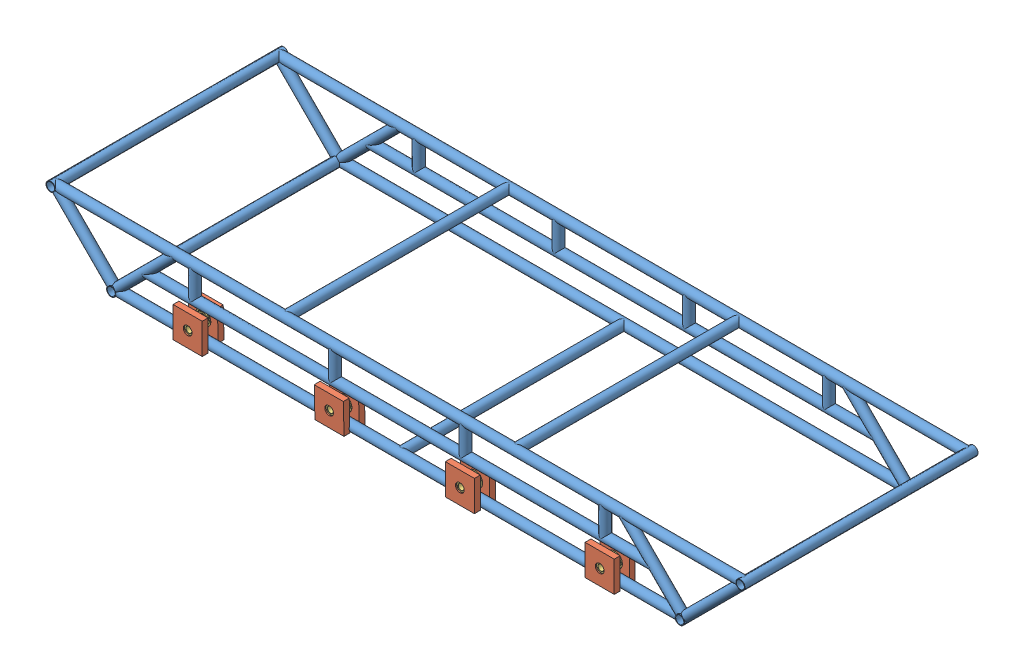
SolidWorks assembly Bodenwanne, configuration Standard. Lengths in mm.
Overall size (1200 120.5 410).
25 component instances, 3 part files, 5 mates.
Components (placement in the parent):
- Ramen Bodenwanne-1: Ramen Bodenwanne [Standard<Wie bearbeitet>] at (-1765.5754 89.1394 1497.5) size (1200 120 400)
- Lagerklotz-1: Lagerklotz [Standard] at (-1456.198 11.0005 1431.2566) x (1 0 0) z (0 -0.027484 0.999622) size (50 52.5 10)
  - Lagerklotz-1: Lagerklotz [Standard] at (-89.1989 -26.6804 47.5) size (50 52.5 10)
  - radial ball bearing_68_din-1: radial ball bearing_68_din [DIN 625 - 6000 - 8,DE,NC,8_68] at (-64.1989 -0.4304 53.5) x (0 0 -1) z (1 0 0) size (8 26 26)
- Lagerklotz-2: Lagerklotz [Standard] at (-1213.9871 4.5623 1431.2898) x (1 0 0) z (0 -0.021338 0.999772) size (50 52.5 10)
  - Lagerklotz-1: Lagerklotz [Standard] at (-89.1989 -26.6804 47.5) size (50 52.5 10)
  - radial ball bearing_68_din-1: radial ball bearing_68_din [DIN 625 - 6000 - 8,DE,NC,8_68] at (-64.1989 -0.4304 53.5) x (0 0 -1) z (1 0 0) size (8 26 26)
- Lagerklotz-3: Lagerklotz [Standard] at (-988.8766 3.3198 1432) size (50 52.5 10)
  - Lagerklotz-1: Lagerklotz [Standard] at (-89.1989 -26.6804 47.5) size (50 52.5 10)
  - radial ball bearing_68_din-1: radial ball bearing_68_din [DIN 625 - 6000 - 8,DE,NC,8_68] at (-64.1989 -0.4304 53.5) x (0 0 -1) z (1 0 0) size (8 26 26)
- Lagerklotz-4: Lagerklotz [Standard] at (-748.8766 3.3198 1432) size (50 52.5 10)
  - Lagerklotz-1: Lagerklotz [Standard] at (-89.1989 -26.6804 47.5) size (50 52.5 10)
  - radial ball bearing_68_din-1: radial ball bearing_68_din [DIN 625 - 6000 - 8,DE,NC,8_68] at (-64.1989 -0.4304 53.5) x (0 0 -1) z (1 0 0) size (8 26 26)
- Lagerklotz-5: Lagerklotz [Standard] at (-1584.5957 3.3198 1563) x (-1 0 0) z (0 0 -1) size (50 52.5 10)
  - Lagerklotz-1: Lagerklotz [Standard] at (-89.1989 -26.6804 47.5) size (50 52.5 10)
  - radial ball bearing_68_din-1: radial ball bearing_68_din [DIN 625 - 6000 - 8,DE,NC,8_68] at (-64.1989 -0.4304 53.5) x (0 0 -1) z (1 0 0) size (8 26 26)
- Lagerklotz-6: Lagerklotz [Standard] at (-1342.3849 3.9862 1562.3073) x (-1 0 0) z (0 0.021338 -0.999772) size (50 52.5 10)
  - Lagerklotz-1: Lagerklotz [Standard] at (-89.1989 -26.6804 47.5) size (50 52.5 10)
  - radial ball bearing_68_din-1: radial ball bearing_68_din [DIN 625 - 6000 - 8,DE,NC,8_68] at (-64.1989 -0.4304 53.5) x (0 0 -1) z (1 0 0) size (8 26 26)
- Lagerklotz-7: Lagerklotz [Standard] at (-1117.2743 3.3198 1563) x (-1 0 0) z (0 0 -1) size (50 52.5 10)
  - Lagerklotz-1: Lagerklotz [Standard] at (-89.1989 -26.6804 47.5) size (50 52.5 10)
  - radial ball bearing_68_din-1: radial ball bearing_68_din [DIN 625 - 6000 - 8,DE,NC,8_68] at (-64.1989 -0.4304 53.5) x (0 0 -1) z (1 0 0) size (8 26 26)
- Lagerklotz-8: Lagerklotz [Standard] at (-877.2743 3.3198 1563) x (-1 0 0) z (0 0 -1) size (50 52.5 10)
  - Lagerklotz-1: Lagerklotz [Standard] at (-89.1989 -26.6804 47.5) size (50 52.5 10)
  - radial ball bearing_68_din-1: radial ball bearing_68_din [DIN 625 - 6000 - 8,DE,NC,8_68] at (-64.1989 -0.4304 53.5) x (0 0 -1) z (1 0 0) size (8 26 26)
Mates (geometry in assembly coordinates):
- Deckungsgleich27: coincident aligned: plane of Lagerklotz-4/Lagerklotz-1 through (-788.0754 29.1394 1489.5) normal (1 0 0); plane of Lagerklotz-8/Lagerklotz-1 through (-788.0754 29.1394 1505.5) normal (1 0 0)
- Deckungsgleich28: coincident aligned: plane of Lagerklotz-3/Lagerklotz-1 through (-1028.0754 29.1394 1489.5) normal (1 0 0); plane of Lagerklotz-7/Lagerklotz-1 through (-1028.0754 29.1394 1505.5) normal (1 0 0)
- Deckungsgleich29: coincident aligned: plane of Lagerklotz-2/Lagerklotz-1 through (-1253.186 29.149 1489.3276) normal (1 0 0); plane of Lagerklotz-6/Lagerklotz-1 through (-1253.186 31.0269 1505.3714) normal (1 0 0)
- Deckungsgleich30: coincident aligned: plane of Lagerklotz-1/Lagerklotz-1 through (-1495.3969 35.23 1489.4445) normal (1 0 0); plane of Lagerklotz-5/Lagerklotz-1 through (-1495.3969 29.1394 1505.5) normal (1 0 0)
- Tangential1: tangent anti-aligned: cylinder of Ramen Bodenwanne-1 through (-737.5754 37.1394 1497.5) axis (-1 0 0) radius 8; plane of Lagerklotz-1/Lagerklotz-1 through (-1545.3969 -17.2502 1488.0015) normal (0 -0.027484 0.999622)
